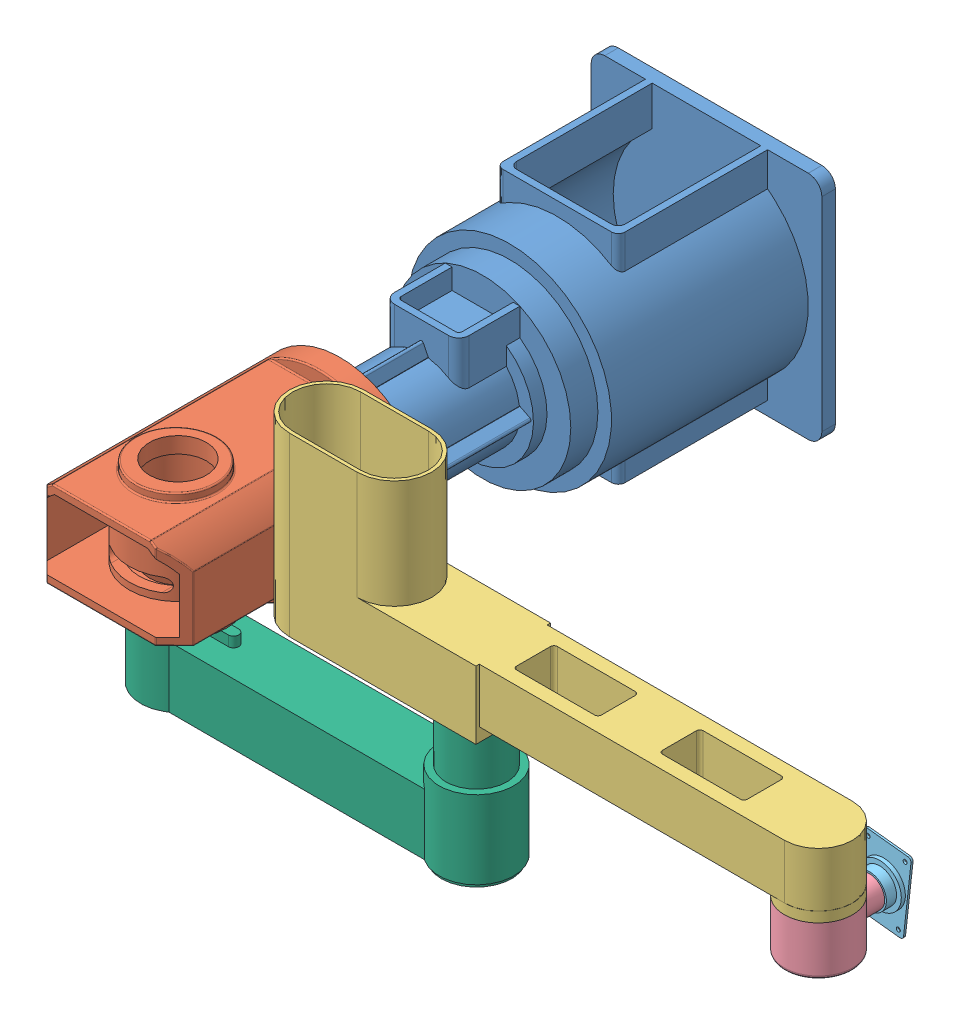
SolidWorks assembly Assem1, configuration Default. Lengths in mm.
Overall size (1164.1 542.35 912).
6 component instances, 6 part files, 14 mates.
Components (placement in the parent):
- Khop_1-1: Khop_1 [Default] at origin size (340 340 560)
- Khop_2-1: Khop_2 [Default] at (0 0 560) size (260 260 352)
- Khop_4-1: Khop_4 [Default<As Machined>] at (440 2.63 799) x (1 0 0) z (0 -1 0) size (830 110 542.35)
- Khop_5-1: Khop_5 [Default] at (944.1005 2.63 799) x (0 0 -1) z (0 -1 0) size (125 100 72.75)
- Khop_6-1: Khop_6 [Default] at (944.1005 2.625 799) x (-0.99399 0.109468 0) z (0 0 -1) size (70 110 24)
- Khop3-1: Khop3 [Default] at (0 2.63 799) x (1 0 0) z (0 -1 0) size (550 110 215)
Mates (geometry in assembly coordinates):
- Coincident1: coincident anti-aligned: plane of Khop_1-1 through (0 0 560) normal (0 0 1); plane of Khop_2-1 through (0 0 560) normal (0 0 -1)
- Concentric2: concentric aligned: cylinder of Khop_1-1 through (0 0 560) axis (0 0 -1) radius 85; cylinder of Khop_2-1 through (0 0 912) axis (0 0 -1) radius 130
- Concentric3: concentric anti-aligned: cylinder of Khop_2-1 through (0 -120 799) axis (0 1 0) radius 52; cylinder of Khop3-1 through (0 -75 799) axis (0 -1 0) radius 55
- Concentric4: concentric aligned: cylinder of Khop_4-1 through (440 114 799) axis (0 -1 0) radius 40; cylinder of Khop3-1 through (440 30 799) axis (0 -1 0) radius 45
- Coincident3: coincident anti-aligned: plane of Khop_4-1 through (444.1005 30 799) normal (0 -1 0); plane of Khop3-1 through (440 30 799) normal (0 1 0)
- Coincident10: coincident anti-aligned: plane of Khop_2-1 through (0 -60 560) normal (0 -1 0); plane of Khop3-1 through (0 -60 799) normal (0 1 0)
- Concentric5: concentric anti-aligned: cylinder of Khop_4-1 through (944.1005 35 799) axis (0 1 0) radius 50; cylinder of Khop_5-1 through (944.1005 35 799) axis (0 -1 0) radius 50
- Coincident11: coincident anti-aligned: plane of Khop_5-1 through (944.1005 2.625 724) normal (0 0 -1); plane of Khop_6-1 through (944.1005 2.625 724) normal (0 0 1)
- Concentric7: concentric aligned: cylinder of Khop_5-1 through (944.1005 2.625 749) axis (0 0 1) radius 22.5; cylinder of Khop_6-1 through (944.1005 2.625 709) axis (0 0 1) radius 25
- Coincident12: coincident anti-aligned: plane of Khop_4-1 through (440 35 799) normal (0 -1 0); plane of Khop_5-1 through (944.1005 35 799) normal (0 1 0)
- Parallel3: parallel aligned: plane of Khop_1-1 through (150 -170 20) normal (0 -1 0); plane of Khop_2-1 through (0 -108 592) normal (0 -1 0)
- Parallel9: parallel aligned: plane of Khop_4-1 through (444.1005 130 849) normal (0 0 1); plane of Khop3-1 through (0 -75 844) normal (0 0 1)
- Parallel11: parallel aligned: plane of Khop_4-1 through (444.1005 130 849) normal (0 0 1); plane of Khop_6-1 through (944.1005 2.625 703) normal (0 0 1)
- Parallel12: parallel aligned: plane of Khop_1-1 through (150 150 20) normal (0 0 1); plane of Khop3-1 through (0 -75 844) normal (0 0 1)
